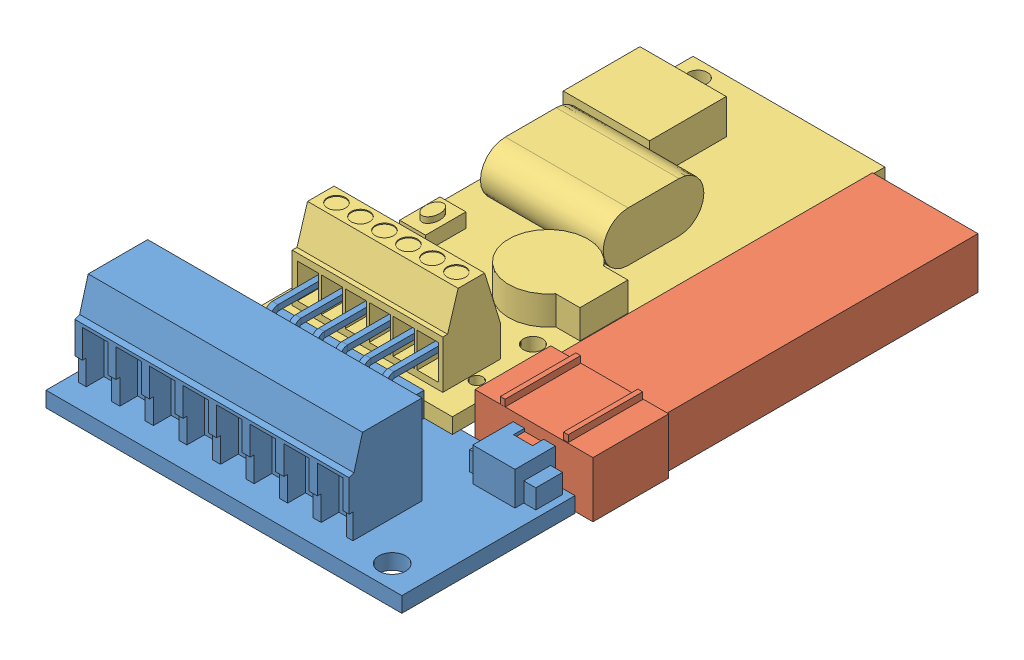
SolidWorks assembly Raven Altimeter Assembly, configuration Default. Lengths in mm.
Overall size (38.9 11.8 62.28).
3 component instances, 3 part files, 4 mates.
Components (placement in the parent):
- Power Perch-1: Power Perch [Default] at origin size (37.1 10.9 21.03)
- 160 mAh Raven Battery-1: 160 mAh Raven Battery [Default] at (27.252 0.1 -58.9246) size (12.3 6.5 43.8)
- Raven 3-1: Raven 3 [Default] at (5.1854 1.6 -17.1846) size (20 10.2 45.1)
Mates (geometry in assembly coordinates):
- Coincident1: coincident anti-aligned: plane of Power Perch-1 through (34.502 2.1 -14.51) normal (-1 0 0); plane of 160 mAh Raven Battery-1 through (34.502 2.1 -15.1246) normal (1 0 0)
- Coincident2: coincident anti-aligned: plane of Power Perch-1 through (31.202 2.1 -14.51) normal (0 1 0); plane of 160 mAh Raven Battery-1 through (31.002 2.1 -15.1246) normal (0 -1 0)
- Coincident3: coincident: plane of Power Perch-1 through (0 1.6 0) normal (0 1 0); plane of Raven 3-1 through (5.1854 1.6 -17.1846) normal (0 -1 0)
- Lock1: lock: unknown of Power Perch-1; unknown of Raven 3-1
